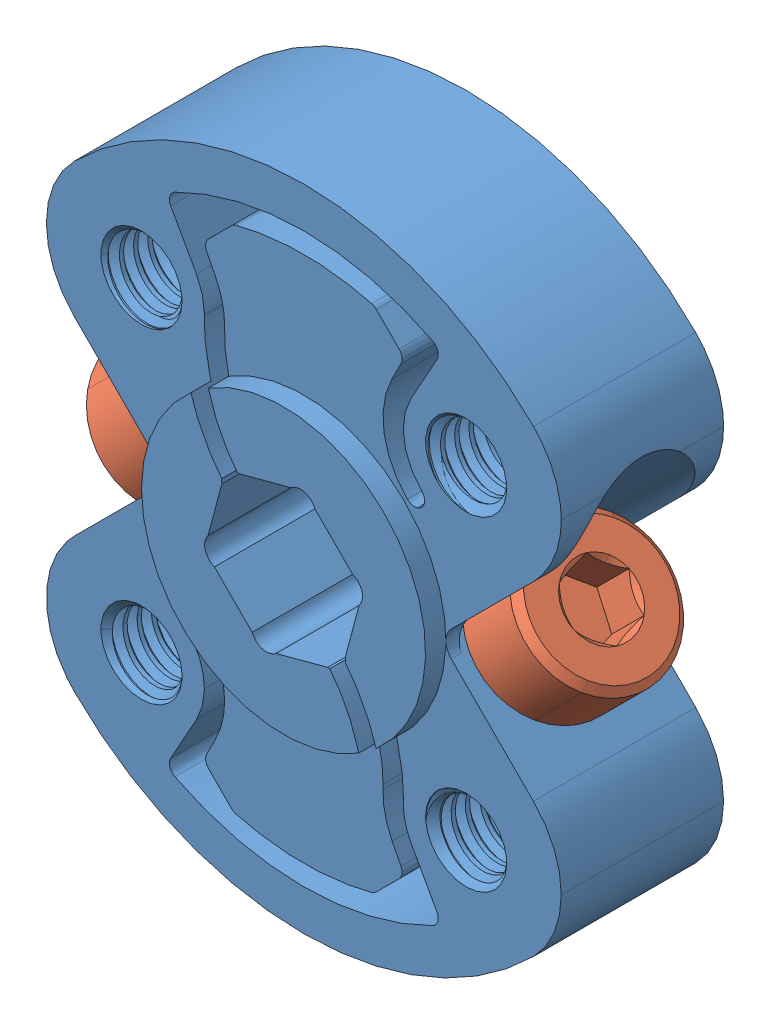
SolidWorks assembly 1309-0016-4008 assembly, configuration Default. Lengths in mm.
Overall size (28.36 32 9.95).
4 component instances, 2 part files, 0 mates.
Components (placement in the parent):
- 1309-0016-4008 assembly.STEP-1: 1309-0016-4008 assembly.STEP [Default] at origin size (28.36 32 9.95)
  - 1309-0016-4008.STEP-1: 1309-0016-4008.STEP [Default] at (-3.9254 17.6745 -10.385) size (25.38 32 9.01)
  - 2800-0004-0014_90128A207.STEP-1: 2800-0004-0014_90128A207.STEP [Default] at (-5.9783 6.5558 -10.385) x (0.5 -0.5 0.707107) z (-0.707107 -0.707107 0) size (7 7 18.01)
  - 2800-0004-0014_90128A207.STEP-2: 2800-0004-0014_90128A207.STEP [Default] at (-1.8726 28.7932 -10.385) x (-0.5 0.5 0.707107) z (0.707107 0.707107 0) size (7 7 18.01)
